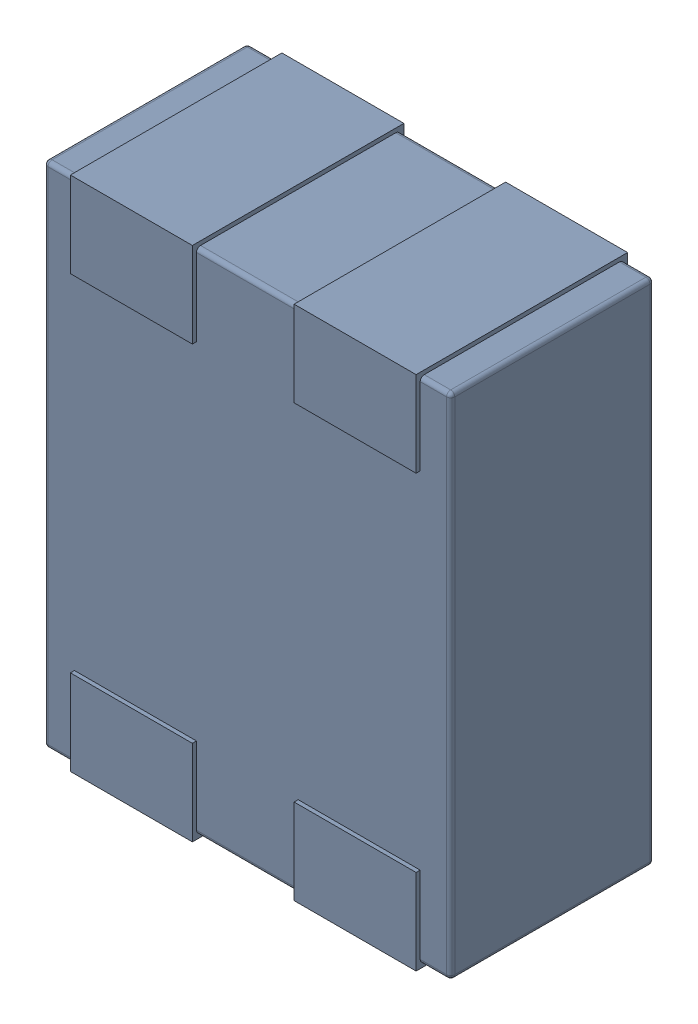
SolidWorks assembly L4, configuration Défaut. Lengths in mm.
Overall size (1 1.27 0.52).
4 component instances, 1 part files, 0 mates.
Components (placement in the parent):
- MCZ1210DH900L2TA0G-1: MCZ1210DH900L2TA0G [Défaut] at (67.893 -33.8195 -1.6) x (-1 0 0) z (0 0 1) size (1 1.27 0.52)
  - 3D_PCB1_2021-12-30 (1).step-1: 3D_PCB1_2021-12-30 (1).step [Défaut] at origin size (1 1.27 0.52)
    - a3ec64f90eb5404ebd79eca0046a794a.step-1: a3ec64f90eb5404ebd79eca0046a794a.step [Défaut] at (5.0419 -6.8961 1.6) size (1 1.27 0.52)
      - SOLID.step_650-1: SOLID.step_650 [Défaut] at origin size (1 1.27 0.52)
